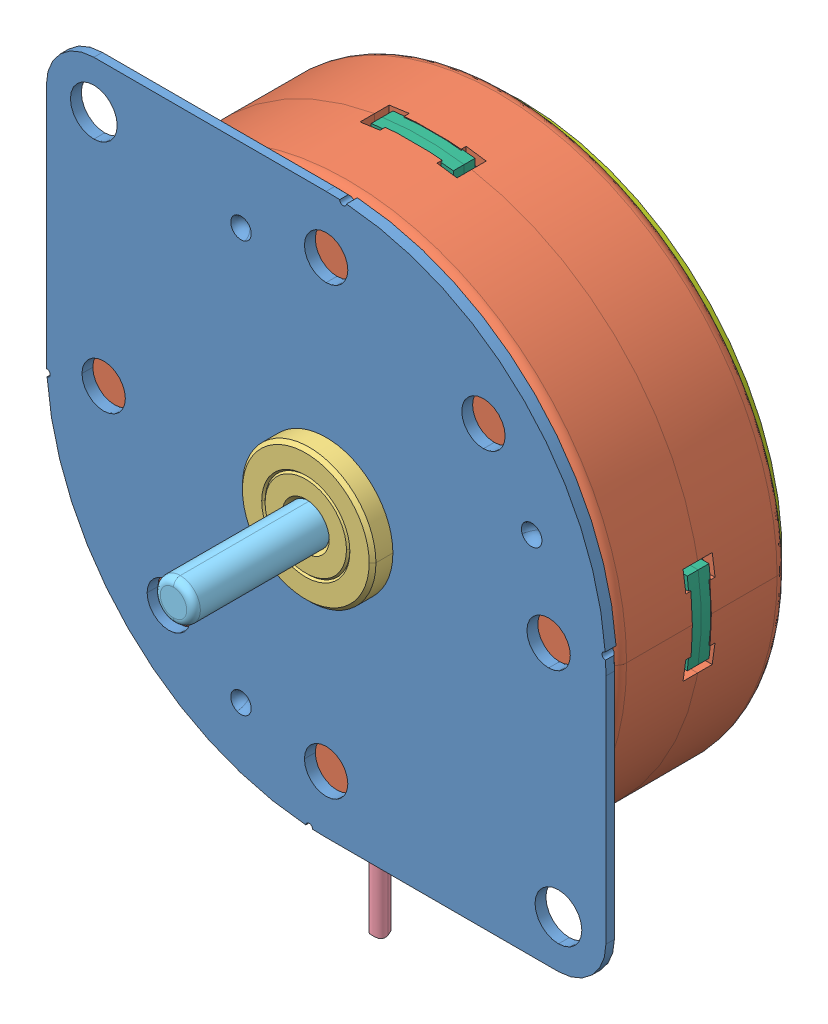
SolidWorks assembly drawing_42m100b, configuration Default. Lengths in mm.
Overall size (59.73 59.73 27.18).
24 component instances, 10 part files, 0 mates.
Components (placement in the parent):
- drawing_42m100b.stp-1: drawing_42m100b.stp [Default] at origin size (59.73 59.73 27.18)
  - 585-5245-001_ASM.stp-1: 585-5245-001_ASM.stp [Default] at (0 0 6.4516) size (41.91 41.91 8.79)
    - 585-5157-001_ASM.stp-1: 585-5157-001_ASM.stp [Default] at origin size (41.91 41.91 7.26)
      - 150-5002-001.stp-1: 150-5002-001.stp [Default] x (0 -1 0) z (0 0 1) size (41.91 41.91 1.37)
      - 053-6016-001.stp-1: 053-6016-001.stp [Default] x (0 0 -1) z (-1 0 0) size (6.45 41.75 41.75)
    - 012-5041-002.stp-1: 012-5041-002.stp [Default] at (0 0 0.6604) x (-1 0 0) z (0 0 -1) size (10 10 3.35)
  - 534-5135_ASM.stp-1: 534-5135_ASM.stp [Default] at (0 0 3.2258) size (2.34 15.34 2.34)
    - 230-0084.stp-1: 230-0084.stp [Default] at (0.5842 -13.208 0.5842) size (1.17 15.34 1.17)
    - 230-0084.stp-2: 230-0084.stp [Default] at (-0.5842 -13.208 -0.5842) size (1.17 15.34 1.17)
  - 534-5135_ASM.stp-2: 534-5135_ASM.stp [Default] at (0 0 -3.2258) x (-1 0 0) z (0 0 -1) size (2.34 15.34 2.34)
    - 230-0084.stp-1: 230-0084.stp [Default] at (0.5842 -13.208 0.5842) size (1.17 15.34 1.17)
    - 230-0084.stp-2: 230-0084.stp [Default] at (-0.5842 -13.208 -0.5842) size (1.17 15.34 1.17)
  - 596-5210-001_ASM.stp-1: 596-5210-001_ASM.stp [Default] at (0 0 18.6944) x (-1 0 0) z (0 0 -1) size (3.05 3.05 27.18)
    - 190-5166-001.stp-1: 190-5166-001.stp [Default] x (-1 0 0) z (0 0 -1) size (3.05 3.05 27.18)
  - 538-6014-001_ASM.stp-1: 538-6014-001_ASM.stp [Default] x (0.866025 -0.5 0) z (0 0 -1) size (56.9 56.9 1.63)
    - 053-6015-002.stp-1: 053-6015-002.stp [Default] x (0 0 1) z (-0.866025 0.5 0) size (0.82 41.66 41.66)
    - 053-6015-002.stp-2: 053-6015-002.stp [Default] x (0 0 -1) z (0.866025 -0.5 0) size (0.82 41.66 41.66)
  - 585-5324-001_ASM.stp-1: 585-5324-001_ASM.stp [Default] at (0 0 -6.4516) x (0 1 0) z (0 0 1) size (41.75 41.75 7.77)
    - 585-6056-001_ASM.stp-1: 585-6056-001_ASM.stp [Default] at origin size (41.75 41.75 7.26)
      - 149-6003-001.stp-1: 149-6003-001.stp [Default] x (-1 0 0) z (0 0 -1) size (39.24 39.24 1.37)
      - 053-6016-001.stp-1: 053-6016-001.stp [Default] x (0 0 1) z (0 -1 0) size (6.45 41.75 41.75)
    - 012-5032-002.stp-1: 012-5032-002.stp [Default] at (0 0 1.524) x (-1 0 0) z (0 0 -1) size (10 10 2.84)
  - 059-5520.stp-1: 059-5520.stp [Default] at (-12.5 4.318 -7.4144) size (25 9 0.15)
  - PRT0001.stp-1: PRT0001.stp [Default] at origin size (40.13 40.13 11.38)
